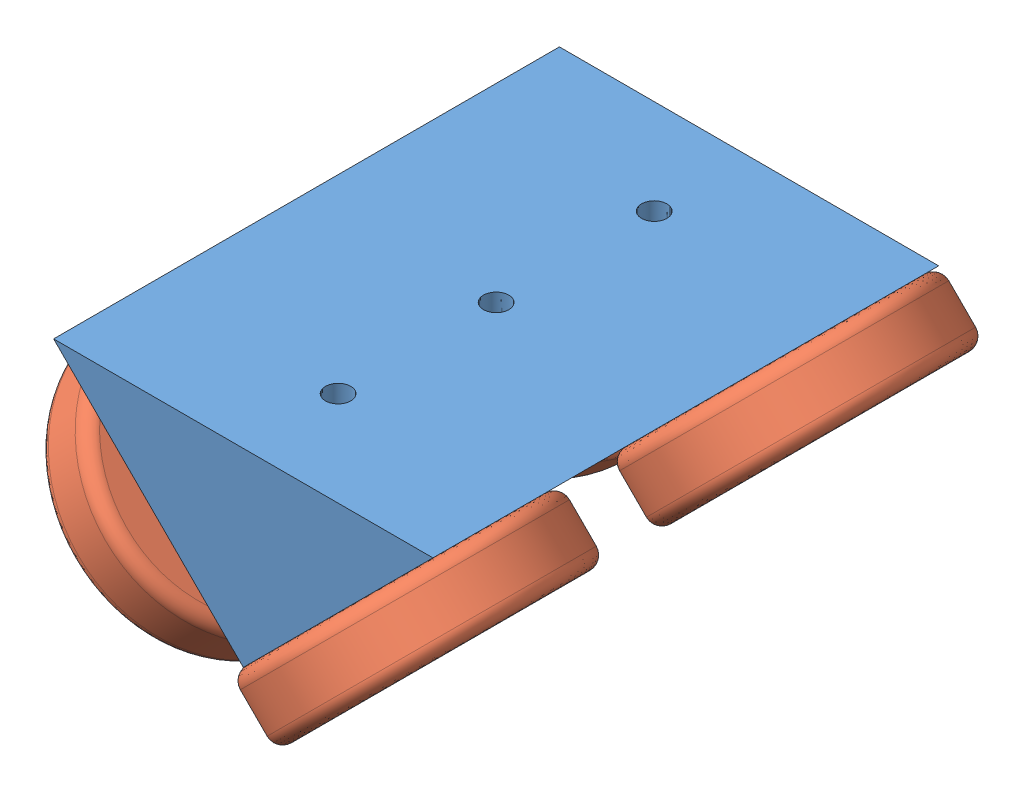
SolidWorks assembly Assem1, configuration Default. Lengths in mm.
Overall size (107.27 62.65 151.7).
5 component instances, 2 part files, 8 mates.
Components (placement in the parent):
- track_hugger-1: track_hugger [Default] at (39.8877 23.5346 -63.9891) size (76.2 38.1 101.6)
- wheel_bearing-1: wheel_bearing [Default] at (-31.442 28.7951 -44.9391) x (0.400895 -0.400895 0.823751) z (0.58248 -0.58248 -0.566952) size (54 12.7 54)
- wheel_bearing-2: wheel_bearing [Default] at (13.4593 19.8148 24.9109) x (-0.400895 -0.400895 0.823751) z (-0.58248 -0.58248 -0.566952) size (54 12.7 54)
- wheel_bearing-3: wheel_bearing [Default] at (-31.442 28.7951 18.5609) x (-0.707106 0.707106 -0.001858) z (-0.001314 0.001314 0.999998) size (54 12.7 54)
- wheel_bearing-4: wheel_bearing [Default] at (4.479 28.7951 -51.2891) x (-0.551896 -0.551896 -0.625156) z (-0.442052 -0.442052 0.780499) size (54 12.7 54)
Mates (geometry in assembly coordinates):
- Coincident5: coincident: plane of track_hugger-1 through (-13.4815 10.8346 37.6109) normal (0.707107 -0.707107 0); plane of wheel_bearing-2 through (4.479 28.7951 24.9109) normal (-0.707107 0.707107 0)
- Coincident6: coincident: plane of track_hugger-1 through (-13.4815 10.8346 37.6109) normal (0.707107 -0.707107 0); plane of wheel_bearing-4 through (4.479 28.7951 -51.2891) normal (-0.707107 0.707107 0)
- Concentric5: concentric anti-aligned: cylinder of track_hugger-1 through (4.479 28.7951 -51.2891) axis (0.707107 -0.707107 0) radius 2.5527; cylinder of wheel_bearing-4 through (13.4593 19.8148 -51.2891) axis (-0.707107 0.707107 0) radius 4
- Concentric6: concentric aligned: cylinder of track_hugger-1 through (4.479 28.7951 24.9109) axis (0.707107 -0.707107 0) radius 2.5527; cylinder of wheel_bearing-2 through (4.479 28.7951 24.9109) axis (0.707107 -0.707107 0) radius 4
- Concentric7: concentric: cylinder of track_hugger-1 through (-31.442 28.7951 18.5609) axis (-0.707107 -0.707107 0) radius 2.5527; cylinder of wheel_bearing-3 through (-40.4223 19.8148 18.5609) axis (0.707107 0.707107 0) radius 4
- Coincident7: coincident anti-aligned: plane of track_hugger-1 through (-51.5815 48.9346 37.6109) normal (-0.707107 -0.707107 0); plane of wheel_bearing-3 through (-31.442 28.7951 18.5609) normal (0.707107 0.707107 0)
- Concentric8: concentric: cylinder of track_hugger-1 through (-31.442 28.7951 -44.9391) axis (-0.707107 -0.707107 0) radius 2.5527; cylinder of wheel_bearing-1 through (-40.4223 19.8148 -44.9391) axis (0.707107 0.707107 0) radius 4
- Coincident8: coincident anti-aligned: plane of track_hugger-1 through (-51.5815 48.9346 37.6109) normal (-0.707107 -0.707107 0); plane of wheel_bearing-1 through (-31.442 28.7951 -44.9391) normal (0.707107 0.707107 0)
